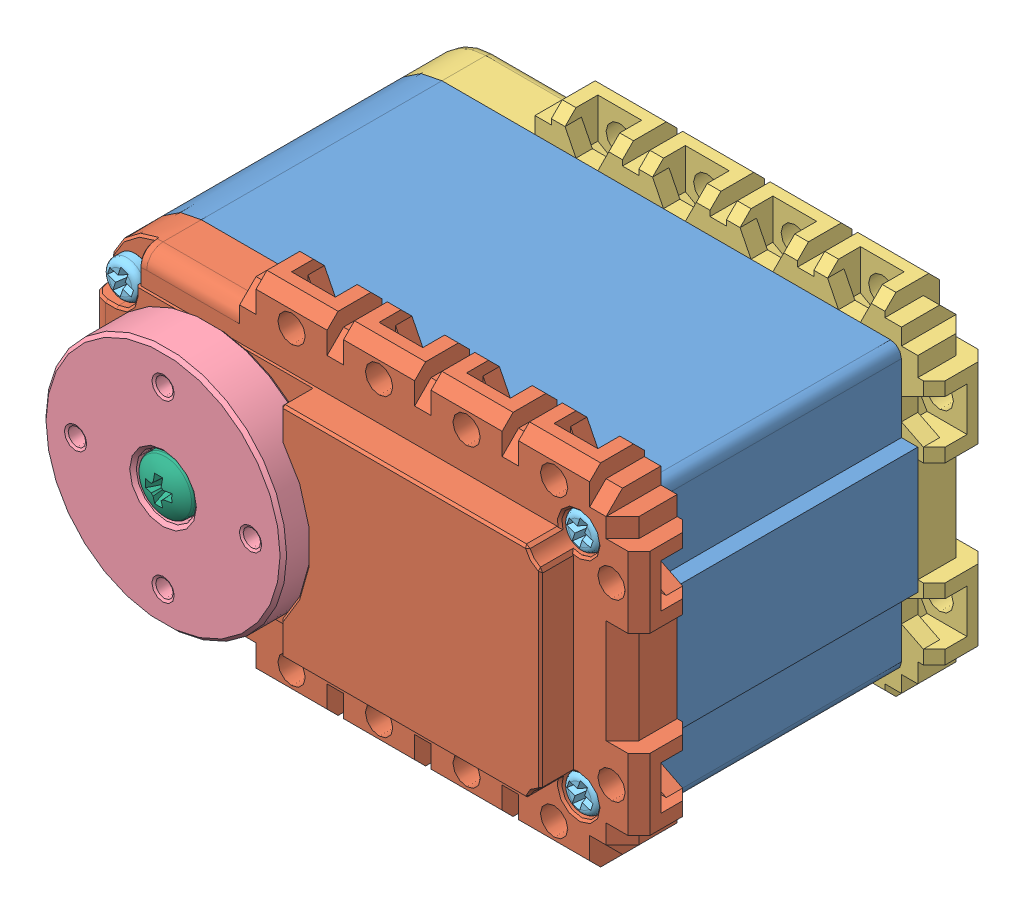
SolidWorks assembly AX-12A, configuration Default. Lengths in mm.
Overall size (50 32 40.55).
9 component instances, 6 part files, 19 mates.
Components (placement in the parent):
- AX-12A-01-1: AX-12A-01 [Default] at origin size (48.5 26 22)
- AX-12A-02-1: AX-12A-02 [Default] at (0 0 13.5) size (50 32 8)
- AX-12A-03-1: AX-12A-03 [Default] at (0 0 -13.5) x (1 0 0) z (0 0 -1) size (50 32 8)
- AX-12A-04-1: AX-12A-04 [Default] at (0 0 21) size (22 22 6.7)
- SetScrew-5: SetScrew [Default] at (33 10.4 14.5) x (0.31498 0.949098 0) z (0 0 -1) size (3.3 3.3 29.44)
- SetScrew-6: SetScrew [Default] at (-9 9.25 14.5) x (0.31498 0.949098 0) z (0 0 -1) size (3.3 3.3 29.44)
- SetScrew-7: SetScrew [Default] at (-9 -9.25 14.5) x (-0.958559 0.284893 0) z (0 0 -1) size (3.3 3.3 29.44)
- SetScrew-8: SetScrew [Default] at (33 -10.4 14.5) x (0.31498 0.949098 0) z (0 0 -1) size (3.3 3.3 29.44)
- pan head cross recess screw_iso-1: pan head cross recess screw_iso [ISO 7045 - M2.5 x 8 - Z --- 8C] at (0 0 21.6) x (0 0 -1) z (1 0 0) size (10.05 5 5)
Mates (geometry in assembly coordinates):
- Coincident1: coincident anti-aligned: plane of AX-12A-01-1 through (0 0 11) normal (0 0 1); plane of AX-12A-02-1 through (0 0 11) normal (0 0 -1)
- Coincident2: coincident aligned: plane of AX-12A-01-1 through (0 0 0) normal (1 0 0); plane of AX-12A-02-1 through (0 0 13.5) normal (1 0 0)
- Coincident3: coincident aligned: plane of AX-12A-01-1 through (0 0 0) normal (0 1 0); plane of AX-12A-02-1 through (0 0 13.5) normal (0 1 0)
- Coincident4: coincident anti-aligned: plane of AX-12A-01-1 through (0 0 -11) normal (0 0 -1); plane of AX-12A-03-1 through (0 0 -11) normal (0 0 1)
- Coincident5: coincident aligned: plane of AX-12A-01-1 through (0 0 0) normal (1 0 0); plane of AX-12A-03-1 through (0 0 -13.5) normal (1 0 0)
- Coincident6: coincident anti-aligned: plane of AX-12A-01-1 through (0 0 0) normal (0 1 0); plane of AX-12A-03-1 through (0 0 -13.5) normal (0 -1 0)
- Concentric1: concentric anti-aligned: cylinder of AX-12A-02-1 through (0 0 13.75) axis (0 0 1) radius 4.75; cylinder of AX-12A-04-1 through (0 0 21) axis (0 0 -1) radius 4.5
- Distance1: distance = 5 mm aligned: plane of AX-12A-02-1 through (0 0 16) normal (0 0 1); plane of AX-12A-04-1 through (0 2.75 21) normal (0 0 1)
- Coincident7: coincident aligned: plane of AX-12A-04-1 through (0 0 21) normal (1 0 0)
- Concentric2: concentric aligned: cylinder of AX-12A-02-1 through (33 10.4 11) axis (0 0 1) radius 1; cylinder of SetScrew-5 through (33 10.4 14.5) axis (0 0 1) radius 0.85
- Coincident8: coincident anti-aligned: plane of AX-12A-02-1 through (0 0 14.5) normal (0 0 1); plane of SetScrew-5 through (33.8067 10.1323 14.5) normal (0 0 -1)
- Concentric3: concentric aligned: cylinder of AX-12A-02-1 through (-9 9.25 11) axis (0 0 1) radius 1; cylinder of SetScrew-6 through (-9 9.25 14.5) axis (0 0 1) radius 0.85
- Coincident9: coincident anti-aligned: plane of AX-12A-02-1 through (0 0 14.5) normal (0 0 1); plane of SetScrew-6 through (-8.1933 8.9823 14.5) normal (0 0 -1)
- Concentric4: concentric aligned: cylinder of AX-12A-02-1 through (-9 -9.25 11) axis (0 0 1) radius 1; cylinder of SetScrew-7 through (-9 -9.25 14.5) axis (0 0 1) radius 0.85
- Coincident10: coincident anti-aligned: plane of AX-12A-02-1 through (0 0 14.5) normal (0 0 1); plane of SetScrew-7 through (-8.7578 -8.4352 14.5) normal (0 0 -1)
- Concentric5: concentric aligned: cylinder of AX-12A-02-1 through (33 -10.4 11) axis (0 0 1) radius 1; cylinder of SetScrew-8 through (33 -10.4 14.5) axis (0 0 1) radius 0.85
- Coincident11: coincident anti-aligned: plane of AX-12A-02-1 through (0 0 14.5) normal (0 0 1); plane of SetScrew-8 through (33.8067 -10.6677 14.5) normal (0 0 -1)
- Concentric71: concentric anti-aligned: cylinder of AX-12A-04-1 through (0 0 21) axis (0 0 -1) radius 2.75; cylinder of pan head cross recess screw_iso-1 through (0 0 47) axis (0 0 1) radius 2.5
- Coincident131: coincident anti-aligned: plane of AX-12A-04-1 through (0 2.75 19.5) normal (0 0 1); plane of pan head cross recess screw_iso-1 through (0 1.25 19.5) normal (0 0 -1)
